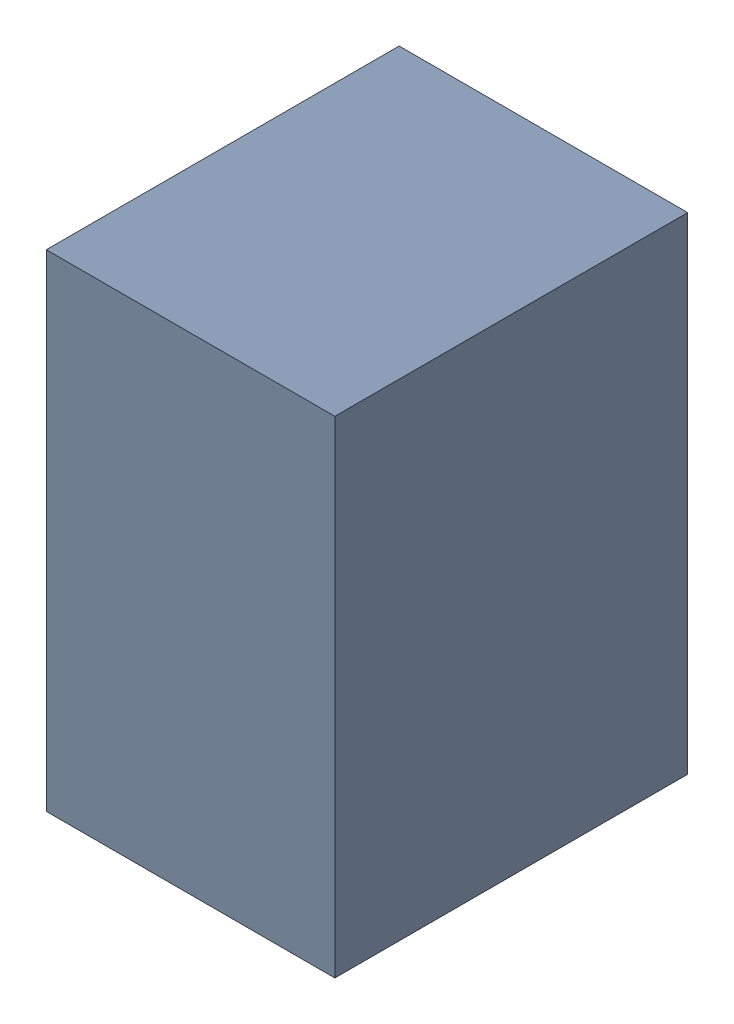
SolidWorks assembly P1, configuration Default. Lengths in mm.
Overall size (8.89 14.99 10.87).
2 component instances, 1 part files, 0 mates.
Components (placement in the parent):
- 743508640-1: 743508640 [Default] at (223.3168 61.2394 0.127) size (8.89 14.99 10.87)
  - Extruded_4-1: Extruded_4 [Default] at origin size (8.89 14.99 10.87)
